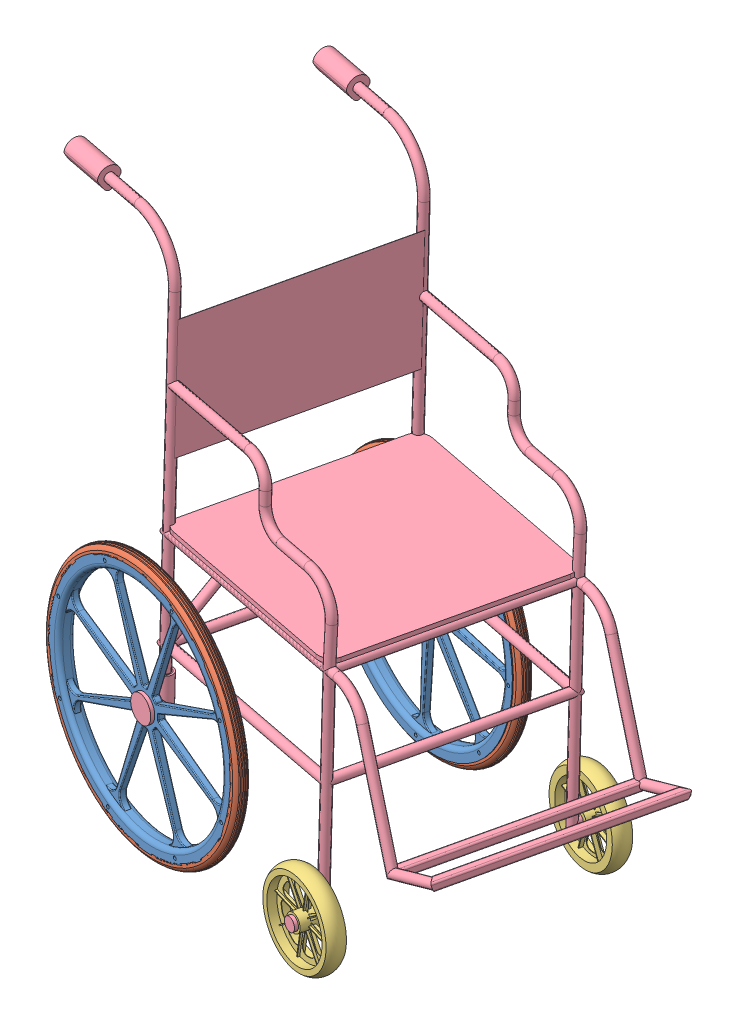
SolidWorks assembly FinalChair, configuration Default. Lengths in mm.
Overall size (1259.12 1314.34 867.96).
7 component instances, 4 part files, 0 mates.
Components (placement in the parent):
- base main-1: base main [Default] at (-1532.3708 -86.5661 2502.5949) x (-0.19279 0.0265 0.980882) z (-0.325918 -0.944612 -0.038538) size (35 546 546)
- Body63-1: Body63 [Default] at (-1173.8313 44.641 1804.9024) x (0.19279 -0.0265 -0.980882) z (0.980882 -0.021792 0.193379) size (31 578 578)
- small tire-1: small tire [Default] at (-1341.6773 108.2135 2417.0618) x (0.19279 -0.0265 -0.980882) z (0.980882 -0.021792 0.193379) size (45 204 204)
- small tire-2: small tire [Default] at (-1066.6811 -876.7425 1970.6455) x (-0.19279 0.0265 0.980882) z (0.907409 0.385233 0.167942) size (45 204 204)
- base main-2: base main [Default] at (-1174.2169 44.694 1806.8641) x (0.19279 -0.0265 -0.980882) z (0.980882 -0.021792 0.193379) size (35 546 546)
- Body63-2: Body63 [Default] at (-1283.529 59.7197 2363.0243) x (0.19279 -0.0265 -0.980882) z (0.980882 -0.021792 0.193379) size (31 578 578)
- FINALCHARON3edit_Default_As Machined_-1: FINALCHARON3edit_Default_As Machined_ [Default] at (-1310.2021 -259.3886 2424.514) x (0.981237 0.002579 0.19279) z (-0.19279 0.0265 0.980882) size (1111.06 1129 636)
